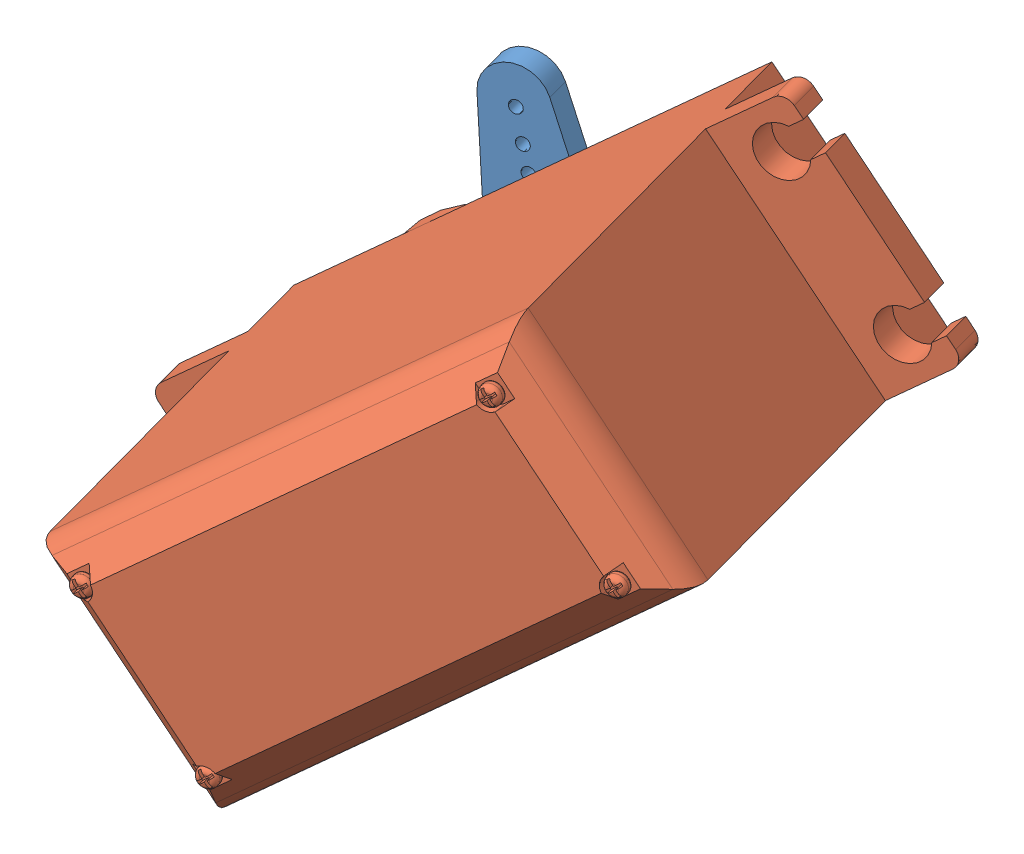
SolidWorks assembly Assem1, configuration Default. Lengths in mm.
Overall size (63.92 51.4 57.71).
2 component instances, 2 part files, 2 mates.
Components (placement in the parent):
- hs-422_horn_2wings_sws-1: hs-422_horn_2wings_sws [Default] at (15.3311 15.6503 18.3768) x (0.928495 0.214873 -0.302863) z (-0.220849 0.975196 0.014811) size (9.1 5 34)
- Standard Servo-1: Standard Servo [Default] at (36.8012 23.6911 54.6372) x (-0.727827 -0.63319 0.263322) z (0.61737 -0.772171 -0.150355) size (53.74 42.63 19.57)
Mates (geometry in assembly coordinates):
- Concentric1: concentric aligned: circle of hs-422_horn_2wings_sws-1; cylinder of Standard Servo-1 through (17.0596 15.958 23.8942) axis (-0.298533 -0.053135 -0.952919) radius 1.27
- Distance1: distance = 6.35 mm aligned: plane of hs-422_horn_2wings_sws-1 through (17.9363 1.4037 16.2562) normal (-0.298533 -0.053135 -0.952919); plane of Standard Servo-1 through (16.6297 15.8815 22.522) normal (-0.298533 -0.053135 -0.952919)
